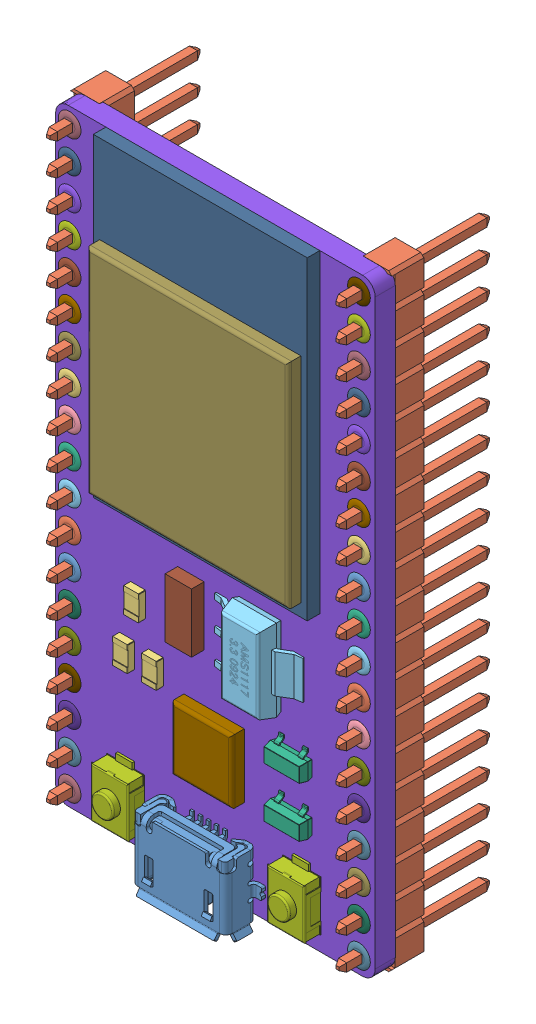
SolidWorks assembly NodeMCU-32S, configuration Default. Lengths in mm.
Overall size (25.55 48.91 13.27).
56 component instances, 50 part files, 0 mates.
Components (placement in the parent):
- NodeMCU-32S.step-1: NodeMCU-32S.step [Default] at origin size (25.55 48.91 13.27)
  - 10104111-0001LF v1.step-1: 10104111-0001LF v1.step [Default] at (0.5 -20.7774 3.2416) x (1 0 0) z (0 -1 0) size (8.81 3.08 5.64)
  - zl201-19_p2-54_l48-3_w2-54_h8-9 v1.step-1: zl201-19_p2-54_l48-3_w2-54_h8-9 v1.step [Default] at (12.1206 22.739 0.2604) x (0 -1 0) z (1 0 0) size (48.26 11.94 2.54)
  - zl201-19_p2-54_l48-3_w2-54_h8-9 v1.step-2: zl201-19_p2-54_l48-3_w2-54_h8-9 v1.step [Default] at (-10.8794 22.739 0.2604) x (0 -1 0) z (1 0 0) size (48.26 11.94 2.54)
  - res_0805 v1.step-1: res_0805 v1.step [Default] at (-6.3396 -11.2378 1.5) x (0 1 0) z (0 0 1) size (2 1.2 0.65)
  - res_1206.step-1: res_1206.step [Default] at origin size (3.2 1.6 0.7)
  - AMS1117 v1.step-1: AMS1117 v1.step [Default] at (4.2592 -6.1564 2.0668) x (0 -1 0) z (-1 0 0) size (6.51 1.86 7)
  - res_0805 v1.step-2: res_0805 v1.step [Default] at (-4.0396 -11.2378 1.5) x (0 1 0) z (0 0 1) size (2 1.2 0.65)
  - res_0805 v1.step-3: res_0805 v1.step [Default] at (-5.4612 -7.301 1.5) x (0 1 0) z (0 0 1) size (2 1.2 0.65)
  - SOT23SMD v1.step-1: SOT23SMD v1.step [Default] at (7.9322 -10.8274 1.6295) x (-1 0 0) z (0 -1 0) size (3 1 2.45)
  - SOT23SMD v1.step-2: SOT23SMD v1.step [Default] at (7.9322 -14.8274 1.6295) x (-1 0 0) z (0 -1 0) size (3 1 2.45)
  - 3x4x2mm - 2 Pad v1.step-1: 3x4x2mm - 2 Pad v1.step [Default] at (7.6223 -21.0215 1.6143) x (0 -1 0) z (0 0 1) size (5 3 1.93)
  - 3x4x2mm - 2 Pad v1.step-2: 3x4x2mm - 2 Pad v1.step [Default] at (-6.3777 -21.0215 1.6143) x (0 -1 0) z (0 0 1) size (5 3 1.93)
  - NodeMCU-32S.step-1: NodeMCU-32S.step [Default] at origin size (25.4 48.26 1.6)
  - NodeMCU-32S-0.step-1: NodeMCU-32S-0.step [Default] at origin size (4.8 5.08 1)
  - NodeMCU-32S-1.step-1: NodeMCU-32S-1.step [Default] at origin size (17 25 1)
  - NodeMCU-32S-2.step-1: NodeMCU-32S-2.step [Default] at origin size (2.1 4.7 1)
  - NodeMCU-32S-3.step-1: NodeMCU-32S-3.step [Default] at origin size (16 17 1)
  - NodeMCU-32S-4.step-1: NodeMCU-32S-4.step [Default] at origin size (1.8 1.8 0.1)
  - NodeMCU-32S-5.step-1: NodeMCU-32S-5.step [Default] at origin size (1.8 1.8 0.1)
  - NodeMCU-32S-6.step-1: NodeMCU-32S-6.step [Default] at origin size (1.8 1.8 0.1)
  - NodeMCU-32S-7.step-1: NodeMCU-32S-7.step [Default] at origin size (1.8 1.8 0.1)
  - NodeMCU-32S-8.step-1: NodeMCU-32S-8.step [Default] at origin size (1.8 1.8 0.1)
  - NodeMCU-32S-9.step-1: NodeMCU-32S-9.step [Default] at origin size (1.8 1.8 0.1)
  - NodeMCU-32S-10.step-1: NodeMCU-32S-10.step [Default] at origin size (1.8 1.8 0.1)
  - NodeMCU-32S-11.step-1: NodeMCU-32S-11.step [Default] at origin size (1.8 1.8 0.1)
  - NodeMCU-32S-12.step-1: NodeMCU-32S-12.step [Default] at origin size (1.8 1.8 0.1)
  - NodeMCU-32S-13.step-1: NodeMCU-32S-13.step [Default] at origin size (1.8 1.8 0.1)
  - NodeMCU-32S-14.step-1: NodeMCU-32S-14.step [Default] at origin size (1.8 1.8 0.1)
  - NodeMCU-32S-15.step-1: NodeMCU-32S-15.step [Default] at origin size (1.8 1.8 0.1)
  - NodeMCU-32S-16.step-1: NodeMCU-32S-16.step [Default] at origin size (1.8 1.8 0.1)
  - NodeMCU-32S-17.step-1: NodeMCU-32S-17.step [Default] at origin size (1.8 1.8 0.1)
  - NodeMCU-32S-18.step-1: NodeMCU-32S-18.step [Default] at origin size (1.8 1.8 0.1)
  - NodeMCU-32S-19.step-1: NodeMCU-32S-19.step [Default] at origin size (1.8 1.8 0.1)
  - NodeMCU-32S-20.step-1: NodeMCU-32S-20.step [Default] at origin size (1.8 1.8 0.1)
  - NodeMCU-32S-21.step-1: NodeMCU-32S-21.step [Default] at origin size (1.8 1.8 0.1)
  - NodeMCU-32S-22.step-1: NodeMCU-32S-22.step [Default] at origin size (1.8 1.8 0.1)
  - NodeMCU-32S-23.step-1: NodeMCU-32S-23.step [Default] at origin size (1.8 1.8 0.1)
  - NodeMCU-32S-24.step-1: NodeMCU-32S-24.step [Default] at origin size (1.8 1.8 0.1)
  - NodeMCU-32S-25.step-1: NodeMCU-32S-25.step [Default] at origin size (1.8 1.8 0.1)
  - NodeMCU-32S-26.step-1: NodeMCU-32S-26.step [Default] at origin size (1.8 1.8 0.1)
  - NodeMCU-32S-27.step-1: NodeMCU-32S-27.step [Default] at origin size (1.8 1.8 0.1)
  - NodeMCU-32S-28.step-1: NodeMCU-32S-28.step [Default] at origin size (1.8 1.8 0.1)
  - NodeMCU-32S-29.step-1: NodeMCU-32S-29.step [Default] at origin size (1.8 1.8 0.1)
  - NodeMCU-32S-30.step-1: NodeMCU-32S-30.step [Default] at origin size (1.8 1.8 0.1)
  - NodeMCU-32S-31.step-1: NodeMCU-32S-31.step [Default] at origin size (1.8 1.8 0.1)
  - NodeMCU-32S-32.step-1: NodeMCU-32S-32.step [Default] at origin size (1.8 1.8 0.1)
  - NodeMCU-32S-33.step-1: NodeMCU-32S-33.step [Default] at origin size (1.8 1.8 0.1)
  - NodeMCU-32S-34.step-1: NodeMCU-32S-34.step [Default] at origin size (1.8 1.8 0.1)
  - NodeMCU-32S-35.step-1: NodeMCU-32S-35.step [Default] at origin size (1.8 1.8 0.1)
  - NodeMCU-32S-36.step-1: NodeMCU-32S-36.step [Default] at origin size (1.8 1.8 0.1)
  - NodeMCU-32S-37.step-1: NodeMCU-32S-37.step [Default] at origin size (1.8 1.8 0.1)
  - NodeMCU-32S-38.step-1: NodeMCU-32S-38.step [Default] at origin size (1.8 1.8 0.1)
  - NodeMCU-32S-39.step-1: NodeMCU-32S-39.step [Default] at origin size (1.8 1.8 0.1)
  - NodeMCU-32S-40.step-1: NodeMCU-32S-40.step [Default] at origin size (1.8 1.8 0.1)
  - NodeMCU-32S-41.step-1: NodeMCU-32S-41.step [Default] at origin size (1.8 1.8 0.1)
